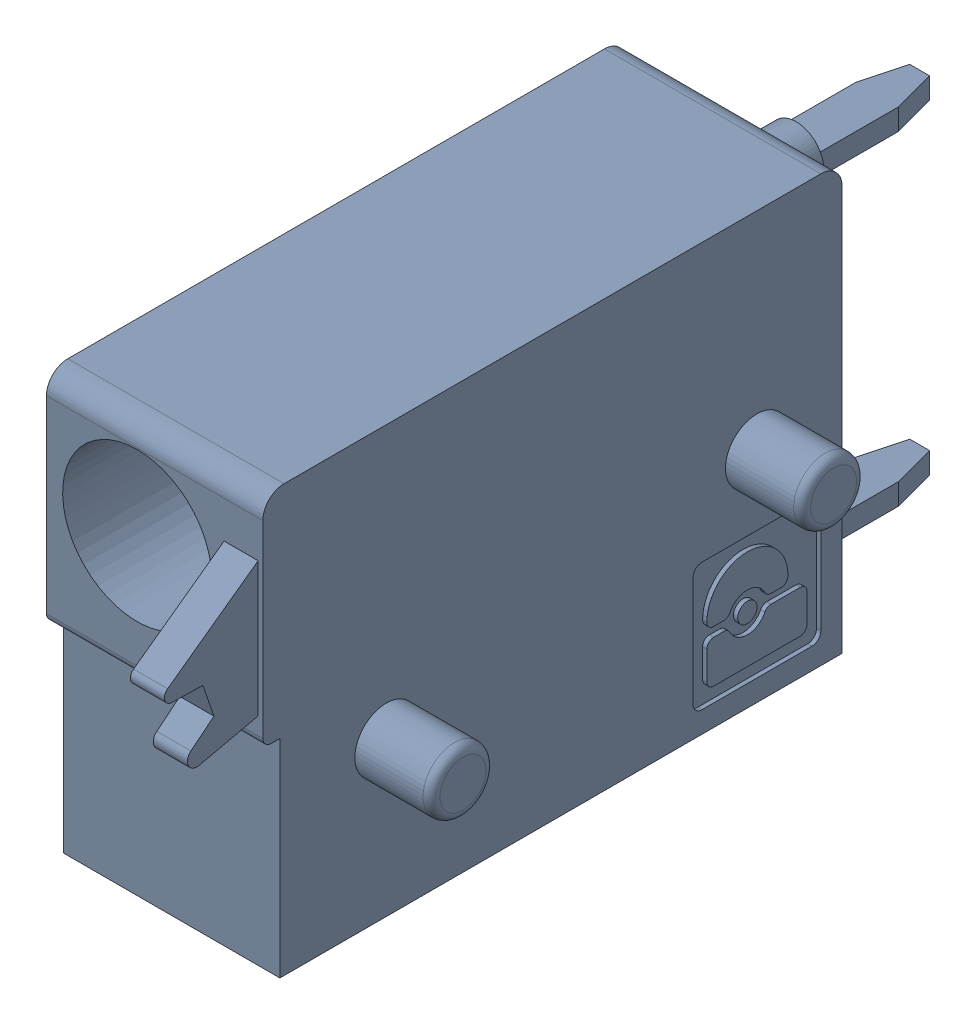
SolidWorks assembly J83, configuration Default. Lengths in mm.
Overall size (6.88 10 19.2).
2 component instances, 1 part files, 0 mates.
Components (placement in the parent):
- 1790348-1: 1790348 [Default] at (238.1251 -7.6199 0) x (0 1 0) z (1 0 0) size (10 19.2 6.88)
  - ffkds-v2-5.08-1: ffkds-v2-5.08 [Default] at (-23.7414 -38.158 -2.54) x (0 -1 0) z (0 0 1) size (19.2 10 6.88)
